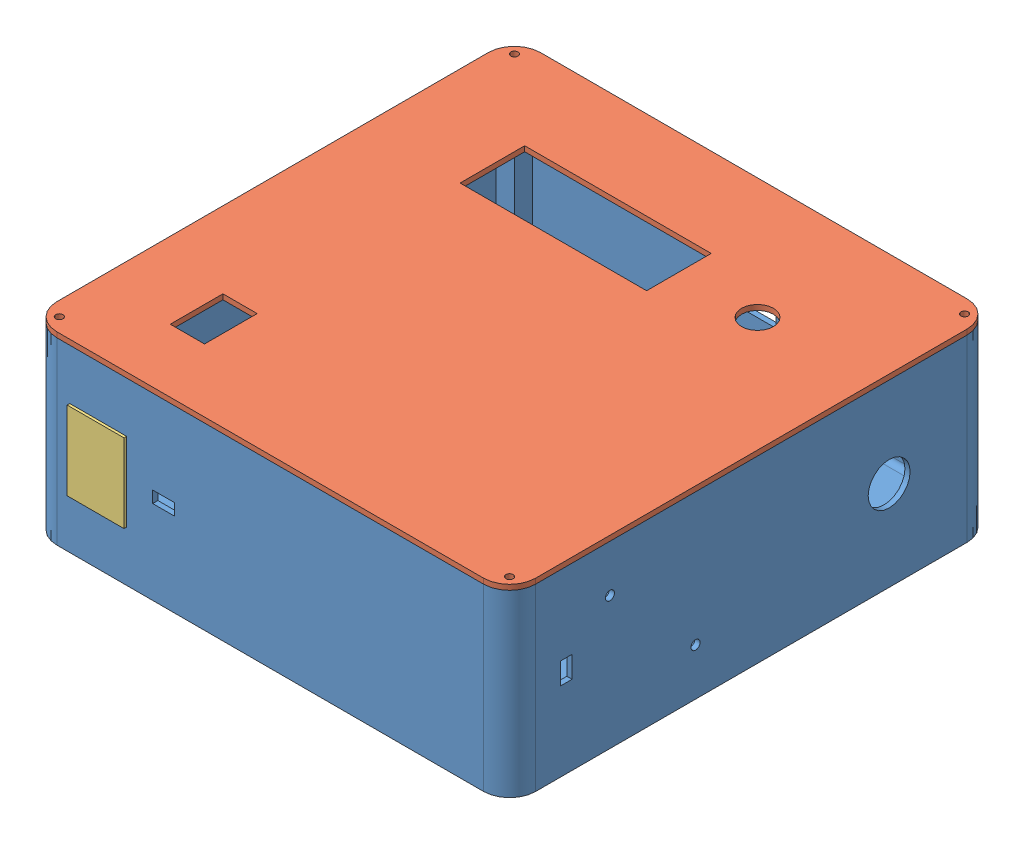
SolidWorks assembly PFIP Assem, configuration Default. Lengths in mm.
Overall size (184 71 186.84).
3 component instances, 3 part files, 6 mates.
Components (placement in the parent):
- PFIP Enclosure Body-1: PFIP Enclosure Body [Default] at (60.0806 67.5238 146.8414) size (184 69 185.84)
- PFIP Enclosure Cover-1: PFIP Enclosure Cover [Default] at (60.0806 132.5238 146.8414) x (-1 0 0) z (0 0 1) size (184 4 185.84)
- PFIP Slot Cover-1: PFIP Slot Cover [Default] at (-5.9944 98.0238 240.7614) x (1 0 0) z (0 1 0) size (21.85 3 30.2)
Mates (geometry in assembly coordinates):
- Concentric1: concentric aligned: circle of PFIP Enclosure Body-1; circle of PFIP Enclosure Cover-1
- Concentric2: concentric aligned: circle of PFIP Enclosure Body-1; circle of PFIP Enclosure Cover-1
- Coincident1: coincident anti-aligned: plane of PFIP Enclosure Body-1 through (60.0806 132.5238 146.8414) normal (0 1 0); plane of PFIP Enclosure Cover-1 through (60.0806 132.5238 146.8414) normal (0 -1 0)
- Distance1: distance = 0.3 mm anti-aligned: plane of PFIP Slot Cover-1 through (-16.6194 112.8238 237.7614) normal (0 1 0); plane of PFIP Enclosure Body-1 through (-16.9194 113.1238 53.9204) normal (0 -1 0)
- Distance2: distance = 0.3 mm anti-aligned: plane of PFIP Slot Cover-1 through (-16.6194 83.2238 237.7614) normal (-1 0 0); plane of PFIP Enclosure Body-1 through (-16.9194 113.1238 53.9204) normal (1 0 0)
- Coincident2: coincident anti-aligned: plane of PFIP Enclosure Body-1 through (60.0806 132.5238 239.7614) normal (0 0 1); plane of PFIP Slot Cover-1 through (-5.9944 98.0238 239.7614) normal (0 0 -1)
